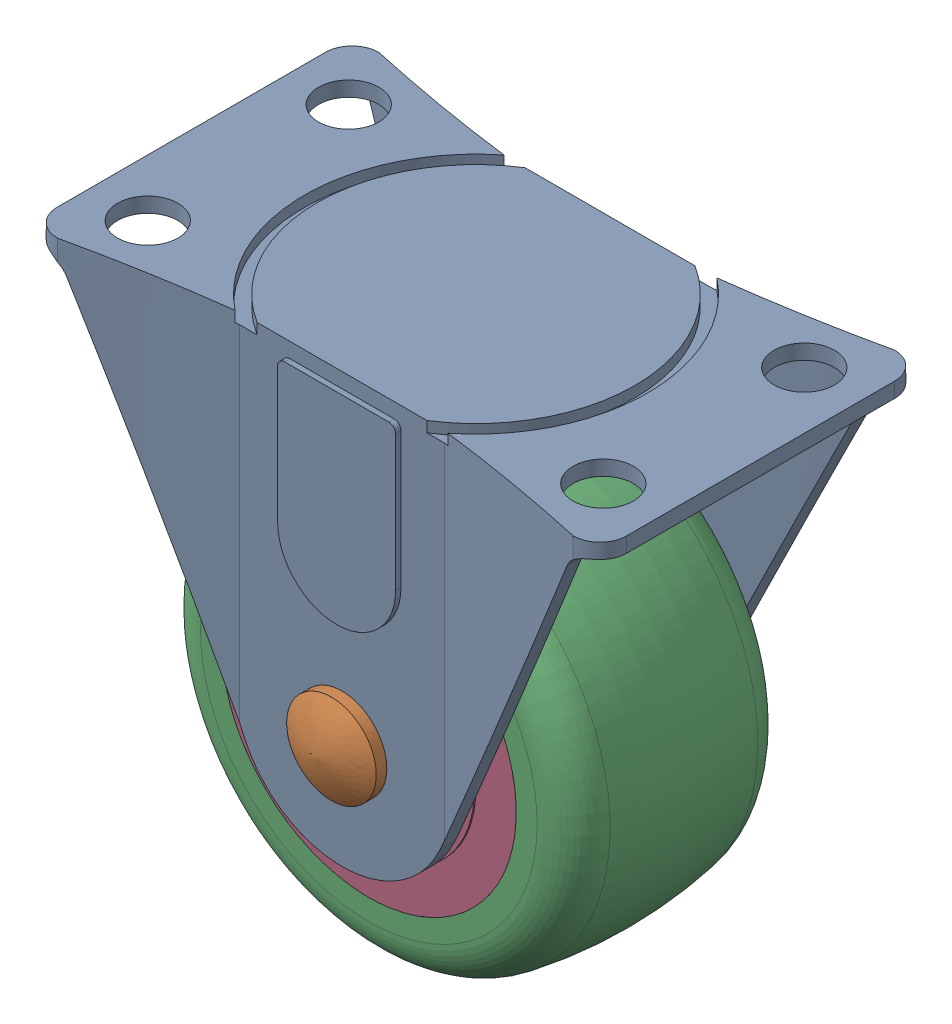
SolidWorks assembly 30POP20R, configuration Default. Lengths in mm.
Overall size (67.46 63.57 38.11).
4 component instances, 4 part files, 0 mates.
Components (placement in the parent):
- 100-20R_R-1: 100-20R_R [Default] at origin size (67.46 50.87 38.11)
- 21.25-A-1: 21.25-A [Default] at (0 -38.1 15.875) size (10.83 10.83 38)
- 21-2x1-T-1: 21-2x1-T [Default] at (0 -38.1 0) size (50.8 50.8 25.75)
- 21-2x1-C-1: 21-2x1-C [Default] at (0 -38.1 0) x (1 0 0) z (0 0 -1) size (35.61 35.61 26.1)
